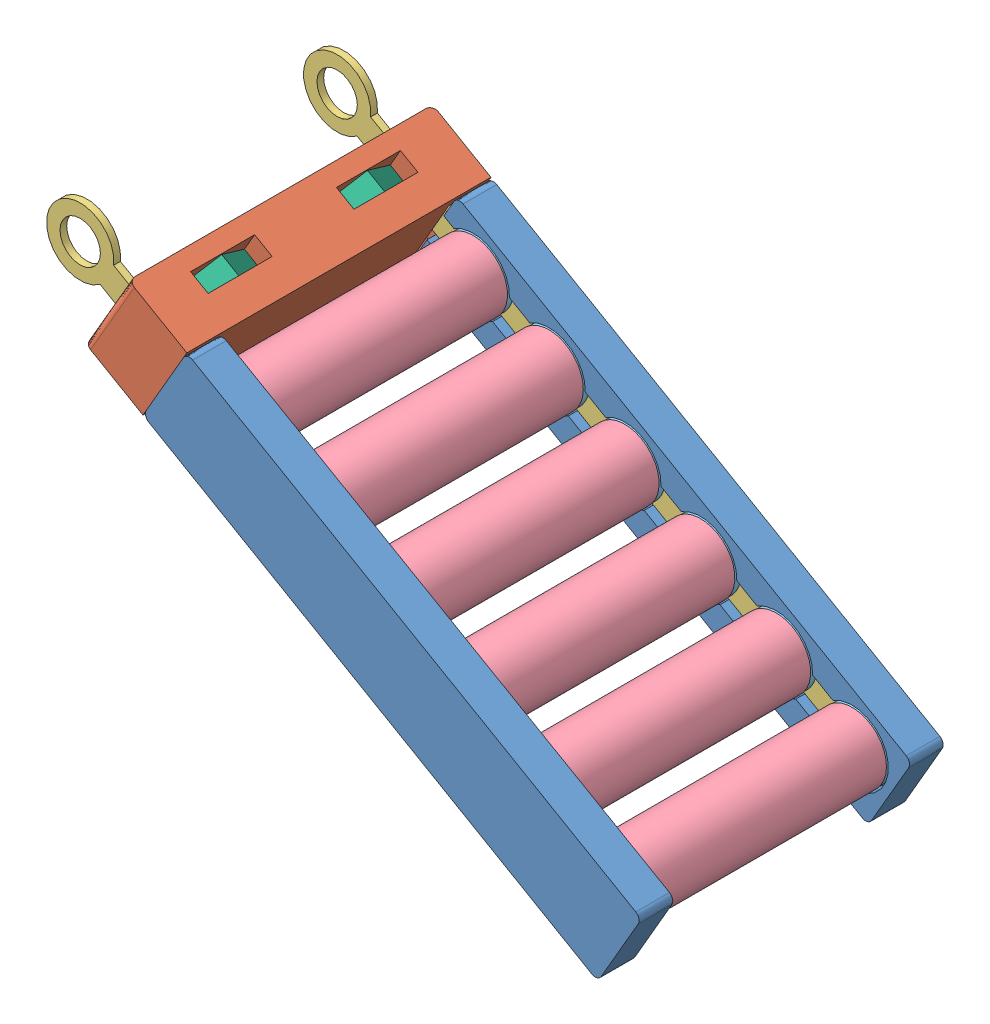
SolidWorks assembly BatteryAssemblyDraft2, configuration Default. Lengths in mm.
Overall size (186.37 121.05 90.3).
25 component instances, 6 part files, 53 mates.
Components (placement in the parent):
- BatteryCover_Draft6-1: BatteryCover_Draft6 [Default] at (109.8488 127.1761 210.9333) x (-0.500686 -0.865629 0) z (0.865629 -0.500686 0) size (26 10 156)
- BatteryCover_Draft6-2: BatteryCover_Draft6 [Default] at (109.8488 127.1761 140.6333) x (0.500686 0.865629 0) z (0.865629 -0.500686 0) size (26 10 156)
- BatteryTopCover-1: BatteryTopCover [Default] at (-31.0349 209.1576 158.626) x (0 0 1) z (-0.500686 -0.865629 0) size (90.3 23 26)
- BatteryBusbar_Draft3-1: BatteryBusbar_Draft3 [Default] at (109.8488 127.1761 136.6333) x (-0.500686 -0.865629 0) z (0.865629 -0.500686 0) size (20 2 199)
- BatteryBusbar_Draft3-2: BatteryBusbar_Draft3 [Default] at (109.8488 127.1761 214.9333) x (0.500686 0.865629 0) z (0.865629 -0.500686 0) size (20 2 199)
- 20700ACell-1: 20700ACell [Default] at (42.3298 166.2296 140.6333) x (-0.383049 0.923728 0) z (0.923728 0.383049 0) size (20.35 70.6 20.35)
- 20700ACell-2: 20700ACell [Default] at (64.8361 153.2118 140.6333) x (-0.383049 0.923728 0) z (0.923728 0.383049 0) size (20.35 70.6 20.35)
- 20700ACell-3: 20700ACell [Default] at (19.8234 179.2475 140.6333) x (-0.999119 -0.041958 0) z (-0.041958 0.999119 0) size (20.35 70.6 20.35)
- 20700ACell-4: 20700ACell [Default] at (109.8488 127.1761 140.6333) x (-0.745379 0.66664 0) z (0.66664 0.745379 0) size (20.35 70.6 20.35)
- 20700ACell-5: 20700ACell [Default] at (-2.6829 192.2653 140.6333) x (-0.383049 0.923728 0) z (0.923728 0.383049 0) size (20.35 70.6 20.35)
- 20700ACell-6: 20700ACell [Default] at (87.3425 140.1939 140.6333) x (0 1 0) z (1 0 0) size (20.35 70.6 20.35)
- PlasticWasher-1: PlasticWasher [Default] at (19.8234 179.2475 138.6333) x (0.001298 -0.999999 0) z (0 0 1) size (20 20 2)
- PlasticWasher-2: PlasticWasher [Default] at (64.8361 153.2118 210.9333) x (0.001298 -0.999999 0) z (0 0 1) size (20 20 2)
- PlasticWasher-3: PlasticWasher [Default] at (109.8488 127.1761 212.9333) x (0.923728 0.383049 0) z (0 0 -1) size (20 20 2)
- PlasticWasher-4: PlasticWasher [Default] at (64.8361 153.2118 140.6333) x (0.923728 0.383049 0) z (0 0 -1) size (20 20 2)
- PlasticWasher-5: PlasticWasher [Default] at (109.8488 127.1761 138.6333) size (20 20 2)
- PlasticWasher-6: PlasticWasher [Default] at (87.3425 140.1939 138.6333) size (20 20 2)
- PlasticWasher-7: PlasticWasher [Default] at (-2.6829 192.2653 140.6333) x (0.923728 0.383049 0) z (0 0 -1) size (20 20 2)
- PlasticWasher-8: PlasticWasher [Default] at (42.3298 166.2296 210.9333) x (-0.923728 -0.383049 0) z (0 0 1) size (20 20 2)
- PlasticWasher-9: PlasticWasher [Default] at (42.3298 166.2296 140.6333) x (0.923728 0.383049 0) z (0 0 -1) size (20 20 2)
- PlasticWasher-10: PlasticWasher [Default] at (-2.6829 192.2653 210.9333) x (0.001298 -0.999999 0) z (0 0 1) size (20 20 2)
- PlasticWasher-11: PlasticWasher [Default] at (19.8234 179.2475 210.9333) x (-0.001298 0.999999 0) z (0 0 1) size (20 20 2)
- PlasticWasher-12: PlasticWasher [Default] at (87.3425 140.1939 210.9333) size (20 20 2)
- HexNut-1: HexNut [Default] at (-26.0729 207.4921 197.4333) x (0.250343 0.432814 -0.866025) z (0.433607 0.749657 0.5) size (21.94 6 19)
- HexNut-2: HexNut [Default] at (-26.0729 207.4921 154.1333) x (0.500686 0.865629 0) z (0 0 1) size (21.94 6 19)
Mates (geometry in assembly coordinates):
- Coincident30: coincident anti-aligned: plane of 20700ACell-4 through (109.8488 127.1761 140.6333) normal (0 0 -1); plane of PlasticWasher-5 through (109.8488 127.1761 140.6333) normal (0 0 1)
- Concentric18: concentric aligned: circle of 20700ACell-4; circle of PlasticWasher-5
- Concentric19: concentric anti-aligned: circle of 20700ACell-4; circle of PlasticWasher-3
- Coincident31: coincident anti-aligned: plane of 20700ACell-4 through (109.8488 127.1761 210.9333) normal (0 0 1); plane of PlasticWasher-3 through (109.8488 127.1761 210.9333) normal (0 0 -1)
- Coincident33: coincident anti-aligned: plane of 20700ACell-6 through (87.3425 140.1939 140.6333) normal (0 0 -1); plane of PlasticWasher-6 through (87.3425 140.1939 140.6333) normal (0 0 1)
- Concentric20: concentric aligned: circle of 20700ACell-6; circle of PlasticWasher-6
- Concentric21: concentric aligned: circle of 20700ACell-6; circle of PlasticWasher-12
- Coincident34: coincident anti-aligned: plane of 20700ACell-6 through (87.3425 140.1939 210.9333) normal (0 0 1); plane of PlasticWasher-12 through (87.3425 140.1939 210.9333) normal (0 0 -1)
- Concentric22: concentric aligned: circle of 20700ACell-2; circle of PlasticWasher-2
- Coincident35: coincident anti-aligned: plane of 20700ACell-2 through (64.8361 153.2118 210.9333) normal (0 0 1); plane of PlasticWasher-2 through (64.8361 153.2118 210.9333) normal (0 0 -1)
- Concentric23: concentric anti-aligned: circle of 20700ACell-2; circle of PlasticWasher-4
- Coincident36: coincident anti-aligned: plane of 20700ACell-2 through (64.8361 153.2118 140.6333) normal (0 0 -1); plane of PlasticWasher-4 through (64.8361 153.2118 140.6333) normal (0 0 1)
- Coincident37: coincident anti-aligned: plane of 20700ACell-1 through (42.3298 166.2296 210.9333) normal (0 0 1); plane of PlasticWasher-8 through (42.3298 166.2296 210.9333) normal (0 0 -1)
- Concentric24: concentric aligned: circle of 20700ACell-1; circle of PlasticWasher-8
- Concentric25: concentric aligned: circle of 20700ACell-3; circle of PlasticWasher-11
- Coincident38: coincident anti-aligned: plane of 20700ACell-3 through (19.8234 179.2475 210.9333) normal (0 0 1); plane of PlasticWasher-11 through (19.8234 179.2475 210.9333) normal (0 0 -1)
- Concentric26: concentric anti-aligned: circle of 20700ACell-1; circle of PlasticWasher-9
- Coincident39: coincident anti-aligned: plane of 20700ACell-1 through (42.3298 166.2296 140.6333) normal (0 0 -1); plane of PlasticWasher-9 through (42.3298 166.2296 140.6333) normal (0 0 1)
- Concentric27: concentric aligned: circle of 20700ACell-3; circle of PlasticWasher-1
- Coincident40: coincident anti-aligned: plane of 20700ACell-3 through (19.8234 179.2475 140.6333) normal (0 0 -1); plane of PlasticWasher-1 through (19.8234 179.2475 140.6333) normal (0 0 1)
- Concentric28: concentric aligned: circle of 20700ACell-5; circle of PlasticWasher-10
- Coincident41: coincident anti-aligned: plane of 20700ACell-5 through (-2.6829 192.2653 210.9333) normal (0 0 1); plane of PlasticWasher-10 through (-2.6829 192.2653 210.9333) normal (0 0 -1)
- Concentric29: concentric anti-aligned: circle of 20700ACell-5; circle of PlasticWasher-7
- Coincident42: coincident anti-aligned: plane of 20700ACell-5 through (-2.6829 192.2653 140.6333) normal (0 0 -1); plane of PlasticWasher-7 through (-2.6829 192.2653 140.6333) normal (0 0 1)
- Coincident43: coincident anti-aligned: plane of BatteryBusbar_Draft3-2 through (109.8488 127.1761 212.9333) normal (0 0 -1); plane of PlasticWasher-3 through (109.8488 127.1761 212.9333) normal (0 0 1)
- Coincident44: coincident anti-aligned: circle of BatteryBusbar_Draft3-2; circle of PlasticWasher-3
- Concentric30: concentric aligned: circle of BatteryBusbar_Draft3-2; circle of PlasticWasher-12
- Coincident47: coincident anti-aligned: plane of BatteryBusbar_Draft3-2 through (109.8488 127.1761 212.9333) normal (0 0 -1); plane of PlasticWasher-12 through (87.3425 140.1939 212.9333) normal (0 0 1)
- Concentric31: concentric aligned: circle of BatteryBusbar_Draft3-2; circle of PlasticWasher-2
- Coincident48: coincident anti-aligned: plane of BatteryBusbar_Draft3-2 through (109.8488 127.1761 212.9333) normal (0 0 -1); plane of PlasticWasher-2 through (64.8361 153.2118 212.9333) normal (0 0 1)
- Concentric32: concentric aligned: circle of BatteryBusbar_Draft3-2; circle of PlasticWasher-8
- Coincident49: coincident anti-aligned: plane of BatteryBusbar_Draft3-2 through (109.8488 127.1761 212.9333) normal (0 0 -1); plane of PlasticWasher-8 through (42.3298 166.2296 212.9333) normal (0 0 1)
- Concentric33: concentric aligned: circle of BatteryBusbar_Draft3-2; circle of PlasticWasher-11
- Coincident51: coincident anti-aligned: plane of BatteryBusbar_Draft3-2 through (109.8488 127.1761 212.9333) normal (0 0 -1); circle of PlasticWasher-11
- Concentric34: concentric aligned: circle of BatteryBusbar_Draft3-2; circle of PlasticWasher-10
- Coincident52: coincident aligned: circle of BatteryBusbar_Draft3-2; plane of PlasticWasher-10 through (-2.6829 192.2653 212.9333) normal (0 0 1)
- Concentric35: concentric anti-aligned: circle of BatteryBusbar_Draft3-1; circle of PlasticWasher-5
- Coincident53: coincident anti-aligned: plane of BatteryBusbar_Draft3-1 through (109.8488 127.1761 138.6333) normal (0 0 1); plane of PlasticWasher-5 through (109.8488 127.1761 138.6333) normal (0 0 -1)
- Concentric36: concentric anti-aligned: circle of BatteryBusbar_Draft3-1; circle of PlasticWasher-6
- Concentric37: concentric anti-aligned: circle of BatteryCover_Draft6-1; circle of BatteryBusbar_Draft3-2
- Coincident55: coincident anti-aligned: plane of BatteryCover_Draft6-1 through (109.8488 127.1761 214.9333) normal (0 0 -1); circle of BatteryBusbar_Draft3-2
- Concentric38: concentric anti-aligned: circle of BatteryCover_Draft6-1; circle of BatteryBusbar_Draft3-2
- Concentric39: concentric anti-aligned: circle of BatteryCover_Draft6-2; circle of BatteryBusbar_Draft3-1
- Coincident58: coincident anti-aligned: plane of BatteryCover_Draft6-2 through (109.8488 127.1761 136.6333) normal (0 0 1); plane of BatteryBusbar_Draft3-1 through (109.8488 127.1761 136.6333) normal (0 0 -1)
- Concentric40: concentric anti-aligned: circle of BatteryCover_Draft6-2; circle of BatteryBusbar_Draft3-1
- Coincident67: coincident anti-aligned: plane of BatteryCover_Draft6-1 through (-13.342 193.8097 216.4333) normal (0.500686 0.865629 0); plane of BatteryTopCover-1 through (-13.342 193.8097 219.9333) normal (-0.500686 -0.865629 0)
- Coincident68: coincident anti-aligned: plane of BatteryCover_Draft6-2 through (-9.3365 200.7347 132.1333) normal (0 0 1); plane of BatteryTopCover-1 through (-13.342 193.8097 132.1333) normal (0 0 -1)
- Coincident77: coincident anti-aligned: plane of BatteryTopCover-1 through (-31.5653 197.9964 187.9333) normal (0 0 1); plane of HexNut-1 through (-18.133 209.2358 187.9333) normal (0 0 -1)
- Coincident78: coincident: plane of BatteryTopCover-1 through (-36.0052 200.5645 158.626) normal (0.500686 0.865629 0); line of HexNut-1 through (-26.3715 194.9923 197.4333) axis (-0.865629 0.500686 0)
- Coincident79: coincident anti-aligned: plane of BatteryTopCover-1 through (-26.3715 194.9923 206.9333) normal (-0.865629 0.500686 0); plane of HexNut-1 through (-20.8792 204.488 197.4333) normal (0.865629 -0.500686 0)
- Coincident80: coincident anti-aligned: plane of BatteryTopCover-1 through (-31.5653 197.9964 163.6333) normal (0.865629 -0.500686 0); plane of HexNut-2 through (-26.0729 207.4921 154.1333) normal (-0.865629 0.500686 0)
- Coincident81: coincident anti-aligned: plane of BatteryTopCover-1 through (-31.5653 197.9964 144.6333) normal (0 0 1); plane of HexNut-2 through (-18.133 209.2358 144.6333) normal (0 0 -1)
- Coincident82: coincident: plane of BatteryTopCover-1 through (-36.0052 200.5645 158.626) normal (0.500686 0.865629 0); line of HexNut-2 through (-26.3715 194.9923 154.1333) axis (-0.865629 0.500686 0)
